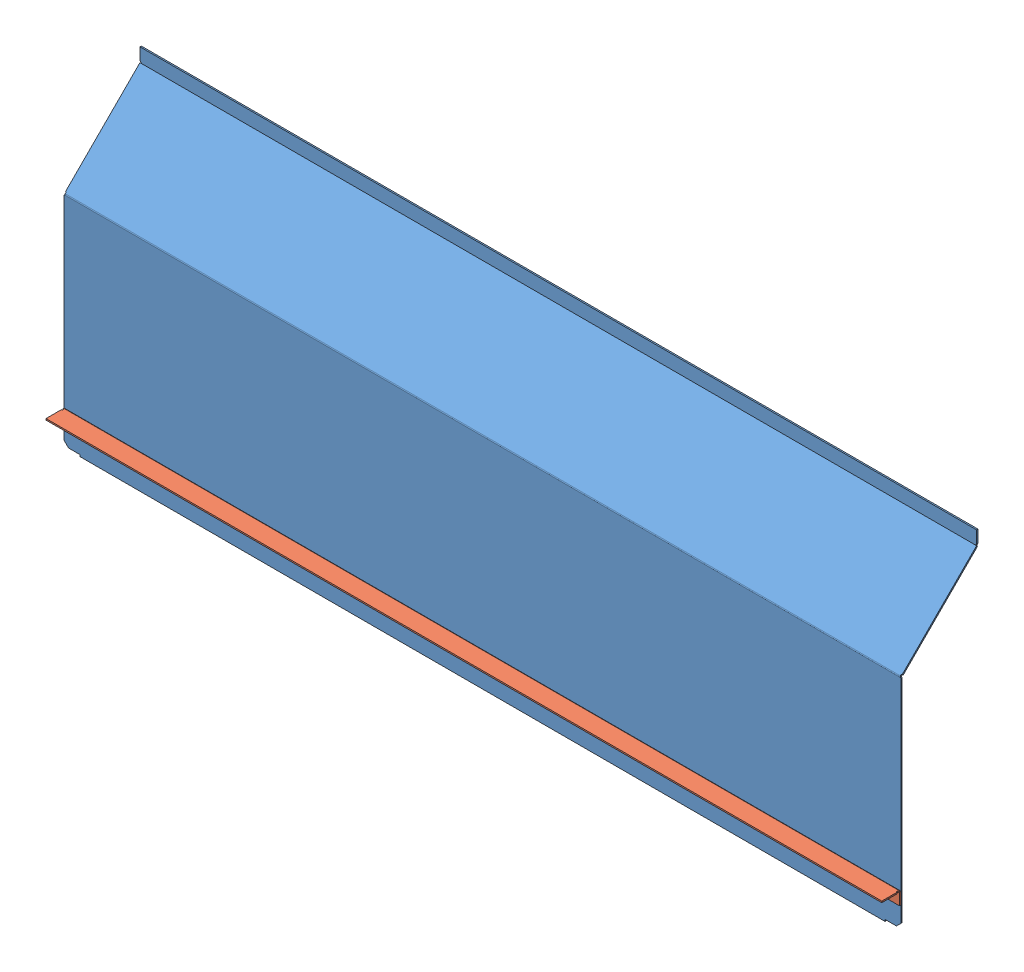
SolidWorks assembly 抽屜導板-2, configuration 預設. Lengths in mm.
Overall size (956 387.73 110.27).
2 component instances, 2 part files, 3 mates.
Components (placement in the parent):
- LB-A54A-02-28-1: LB-A54A-02-28 [預設] at (-81709.8281 17694.6839 42.6882) size (956 387.73 88.58)
- LB-A54-10-4-1: LB-A54-10-4 [預設] at (-85262.1171 17534.7927 44.2882) size (955 14.7 21.69)
Mates (geometry in assembly coordinates):
- 重合/共線/共點1: coincident: plane of LB-A54A-02-28-1 through (479.643 204.2025 44.2882) normal (0 0 1); plane of LB-A54-10-4-1 through (453.5458 -128.5321 44.2882) normal (0 0 -1)
- 重合/共線/共點2: coincident: line of LB-A54A-02-28-1 through (-476.357 -128.5321 42.6882) axis (1 0 0); plane of LB-A54-10-4-1 through (453.5458 -128.5321 47.4802) normal (0 1 0)
- 重合/共線/共點3: coincident aligned: plane of LB-A54A-02-28-1 through (479.643 81.3218 44.2882) normal (1 0 0); plane of LB-A54-10-4-1 through (453.5458 -143.2321 45.8882) normal (1 0 0)
